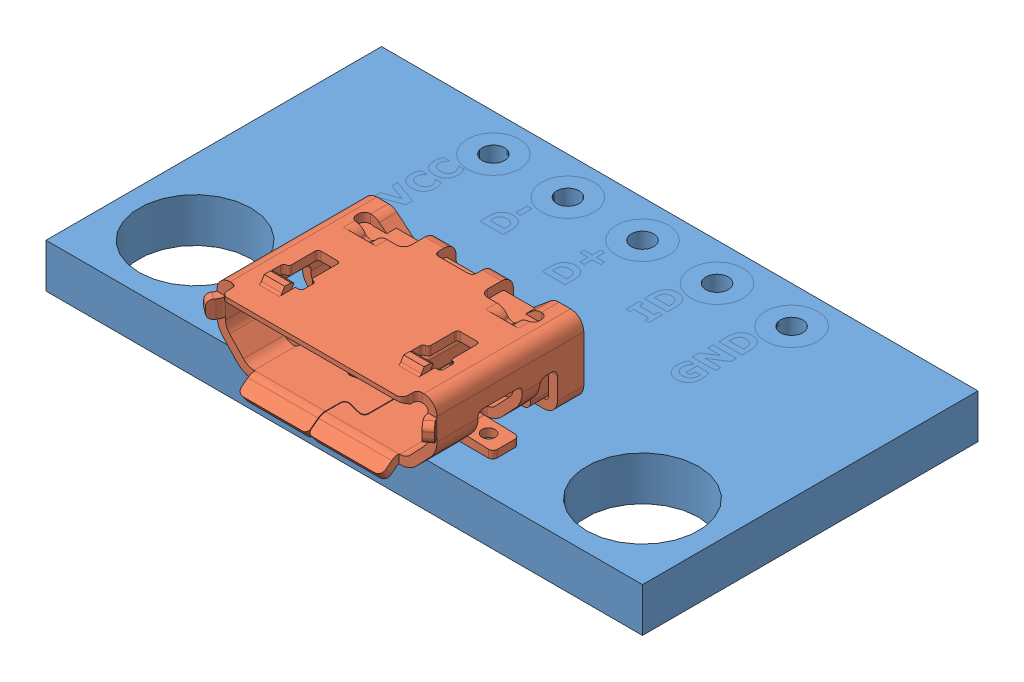
SolidWorks assembly ASM - Breakout Board Micro B, configuration 기본. Lengths in mm.
Overall size (20.32 4.21 12.63).
2 component instances, 2 part files, 3 mates.
Components (placement in the parent):
- Parts - PCB-1: Parts - PCB [기본] at origin size (20.32 1.5 11.43)
- Parts - micro_B-1: Parts - micro_B [기본] at (0 1.125 1.0045) size (7.92 3.01 5.67)
Mates (geometry in assembly coordinates):
- 일치2: coincident anti-aligned: plane of Parts - PCB-1 through (0 1.5 0) normal (0 1 0); plane of Parts - micro_B-1 through (0.9483 1.5 2.4285) normal (0 -1 0)
- 일치3: coincident aligned: plane of Parts - PCB-1 through (0 0 0) normal (1 0 0); plane of Parts - micro_B-1 through (0 1.125 1.0045) normal (1 0 0)
- 거리1: distance = 1.2 mm: line of Parts - micro_B-1 through (0 1.4408 6.915) axis (0 1 0); plane of Parts - PCB-1 through (-10.16 1.5 5.715) normal (0 0 1)
